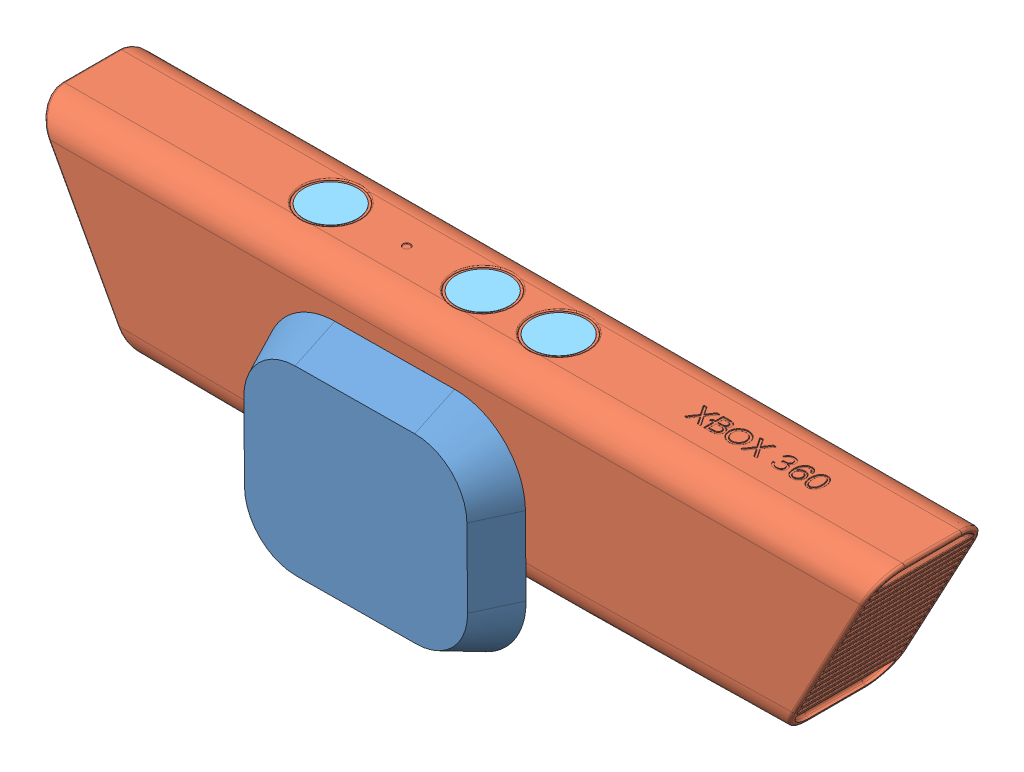
SolidWorks assembly kinect assembly, configuration Default. Lengths in mm.
Overall size (281.71 76.12 72.2).
8 component instances, 5 part files, 10 mates.
Components (placement in the parent):
- kinect base-1: kinect base [Default] at (-20.9932 -5.9594 15.1266) x (-0.999962 -0.008727 0) z (0 0 1) size (89.59 75.34 31.49)
- kinect-1: kinect [Default] at (-162.3863 24.8348 -4.821) x (0.999994 0.003403 0) z (0 0 -1) size (281.5 63.66 39.74)
- kinect pivot-2: kinect pivot [Default] at (-20.9932 -5.9594 11.8478) x (0 1 0) z (0 0 -1) size (25.4 25.4 32.54)
- kinect middle lightbulb-1: kinect middle lightbulb [Default] at (-30.8691 22.0262 -23.871) x (0.990755 0.003371 0.135623) z (-0.003403 0.999994 0) size (3.17 3.17 1.59)
- kinect middle lightbulb-2: kinect middle lightbulb [Default] at (-5.4695 22.1937 -23.871) x (0.999071 0.003399 0.042963) z (-0.003403 0.999994 0) size (3.17 3.17 1.59)
- kinect lens cover-1: kinect lens cover [Default] at (-81.6785 24.7125 -23.871) x (0.999994 0.003403 -0.000631) z (-0.003403 0.999994 0) size (17.78 17.78 0.1)
- kinect lens cover-2: kinect lens cover [Default] at (-30.8792 24.9846 -23.871) x (0.999994 0.003403 -0.000388) z (0.003403 -0.999994 0) size (17.78 17.78 0.1)
- kinect lens cover-3: kinect lens cover [Default] at (-5.4793 25.071 -23.871) x (0.999994 0.003403 -0.000677) z (0.003403 -0.999994 0) size (17.78 17.78 0.1)
Mates (geometry in assembly coordinates):
- Concentric3: concentric aligned: circle of kinect base-1; circle of kinect pivot-2
- Concentric4: concentric anti-aligned: circle of kinect-1; circle of kinect pivot-2
- Coincident8: coincident anti-aligned: plane of kinect-1 through (-20.9932 -5.9594 -7.996) normal (0 0 1); plane of kinect pivot-2 through (-20.9932 -5.9594 -7.996) normal (0 0 -1)
- Concentric5: concentric aligned: circle of kinect-1; circle of kinect middle lightbulb-1
- Coincident10: coincident aligned: circle of kinect-1; circle of kinect middle lightbulb-2
- Coincident11: coincident aligned: circle of kinect-1; circle of kinect lens cover-1
- Coincident12: coincident anti-aligned: plane of kinect-1 through (-30.8788 24.8854 -23.871) normal (-0.003403 0.999994 0); plane of kinect lens cover-2 through (-30.8788 24.8854 -23.871) normal (0.003403 -0.999994 0)
- Concentric8: concentric anti-aligned: circle of kinect-1; circle of kinect lens cover-2
- Coincident13: coincident anti-aligned: plane of kinect-1 through (-5.479 24.9718 -23.871) normal (-0.003403 0.999994 0); plane of kinect lens cover-3 through (-5.479 24.9718 -23.871) normal (0.003403 -0.999994 0)
- Concentric9: concentric anti-aligned: circle of kinect-1; circle of kinect lens cover-3
